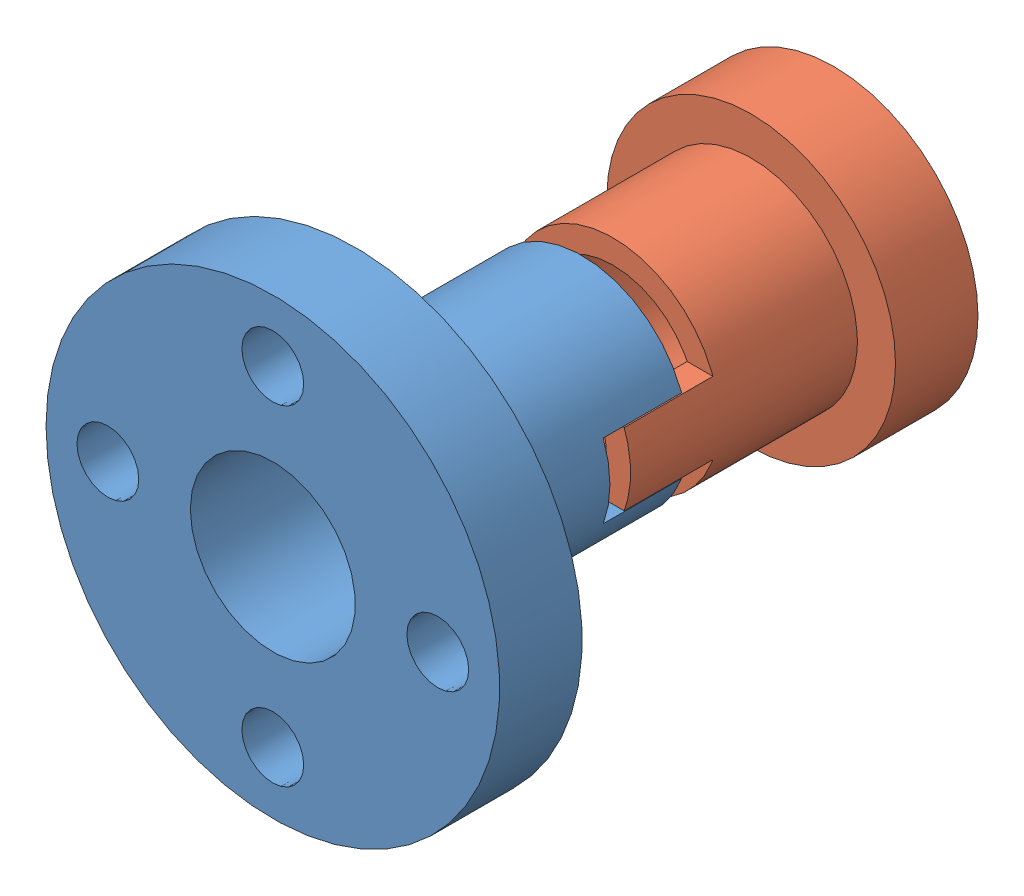
SolidWorks assembly T8消回差螺母, configuration 默认. Lengths in mm.
Overall size (22 22 27.2).
2 component instances, 2 part files, 3 mates.
Components (placement in the parent):
- T8消回差螺母-part1-1: T8消回差螺母-part1 [默认] at origin size (22 22 15)
- T8消回差螺母-part2-1: T8消回差螺母-part2 [默认] at (0 0 -19.2) x (-1 0 0) z (0 0 -1) size (14 14 15)
Mates (geometry in assembly coordinates):
- 距离1: distance = 1 mm: plane of assembly; plane of assembly; plane of T8消回差螺母-part1-1 through (11 1.8 -7.2) normal (0 0 -1); plane of T8消回差螺母-part2-1 through (0 0 -8.2) normal (0 0 1)
- 同心1: concentric: cylinder of assembly; cylinder of assembly; cylinder of T8消回差螺母-part1-1 through (0 0 4) axis (0 0 -1) radius 4; cylinder of T8消回差螺母-part2-1 through (0 0 -23.2) axis (0 0 1) radius 4
- 平行1: parallel: plane of assembly; plane of assembly; plane of T8消回差螺母-part1-1 through (11 -1.8 -11) normal (0 1 0); plane of T8消回差螺母-part2-1 through (7 -1.75 -8.2) normal (0 -1 0)
